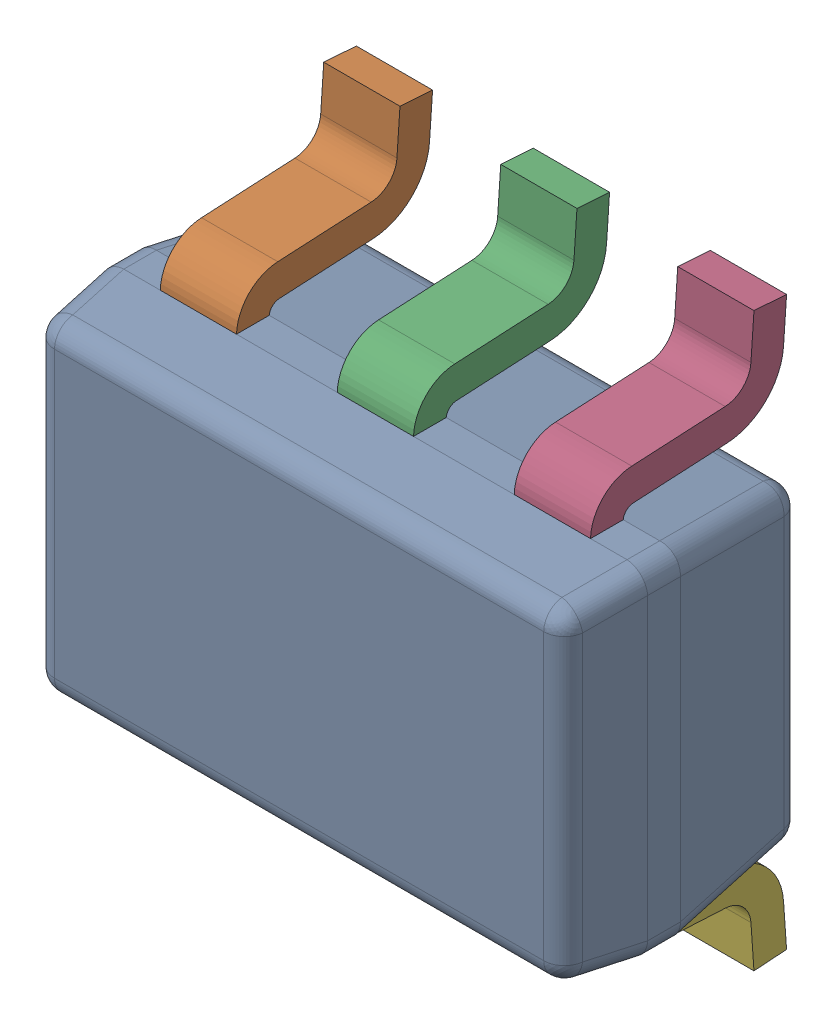
SolidWorks assembly U7, configuration ﾃﾞﾌｫﾙﾄ. Lengths in mm.
Overall size (2 2.1 1.01).
7 component instances, 2 part files, 0 mates.
Components (placement in the parent):
- DCK0005A-1: DCK0005A [ﾃﾞﾌｫﾙﾄ] at (56.7 35 0) x (0 -1 0) z (0 0 1) size (2.1 2 1.01)
  - BODY-SOT_2-1: BODY-SOT_2 [ﾃﾞﾌｫﾙﾄ] at (0 0 0.72) x (0 -1 0) z (-1 0 0) size (2 0.92 1.25)
  - LEAD-SOT_2-1: LEAD-SOT_2 [ﾃﾞﾌｫﾙﾄ] at (-0.6816 -0.65 0.15) x (0 -1 0) z (-1 0 0) size (0.28 0.72 0.43)
  - LEAD-SOT_2-2: LEAD-SOT_2 [ﾃﾞﾌｫﾙﾄ] at (-0.6816 0 0.15) x (0 -1 0) z (-1 0 0) size (0.28 0.72 0.43)
  - LEAD-SOT_2-3: LEAD-SOT_2 [ﾃﾞﾌｫﾙﾄ] at (-0.6816 0.65 0.15) x (0 -1 0) z (-1 0 0) size (0.28 0.72 0.43)
  - LEAD-SOT_2-4: LEAD-SOT_2 [ﾃﾞﾌｫﾙﾄ] at (0.6816 -0.65 0.15) x (0 1 0) z (1 0 0) size (0.28 0.72 0.43)
  - LEAD-SOT_2-5: LEAD-SOT_2 [ﾃﾞﾌｫﾙﾄ] at (0.6816 0.65 0.15) x (0 1 0) z (1 0 0) size (0.28 0.72 0.43)
